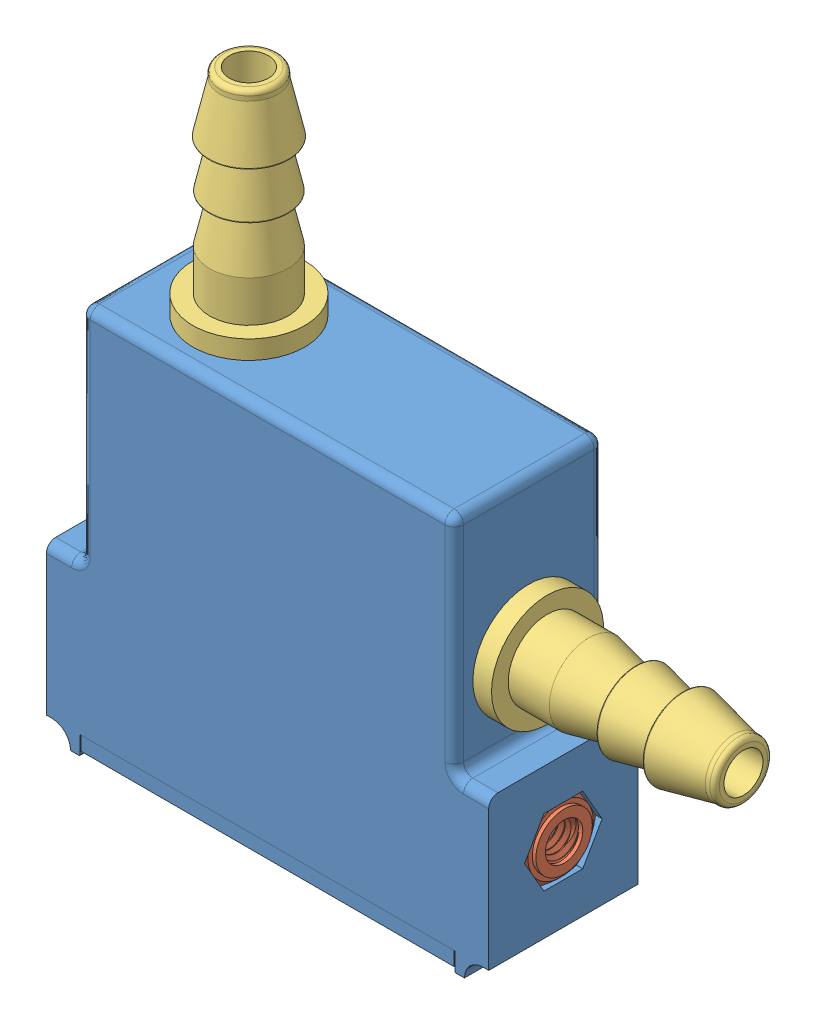
SolidWorks assembly Thermal_Block_Half_Assembly_P, configuration Default. Lengths in mm.
Overall size (66.78 65 16.85).
5 component instances, 3 part files, 8 mates.
Components (placement in the parent):
- Thermal_Block_Half_P-1: Thermal_Block_Half_P [Default] at (18.4797 6.8646 35.2017) size (47.4 42 16)
- M4 x 0.7 Hex Nut-1: M4 x 0.7 Hex Nut [90592A090] at (40.2797 14.8646 35.2017) x (0 -1 0) z (0 0 1) size (7 3.86 8.08)
- M4 x 0.7 Hex Nut-2: M4 x 0.7 Hex Nut [90592A090] at (-3.3203 14.8646 35.2017) x (0 1 0) z (0 0 1) size (7 3.86 8.08)
- Tube_Fitting_Final-1: Tube_Fitting_Final [Default] at (40.4797 30.8646 35.2017) x (1 0 0) z (0 0.787568 -0.616227) size (23 12 12)
- Tube_Fitting_Final-2: Tube_Fitting_Final [Default] at (8.4797 48.8646 35.2017) x (0 1 0) z (0 0 1) size (23 12 12)
Mates (geometry in assembly coordinates):
- Coincident1: coincident anti-aligned: plane of Thermal_Block_Half_P-1 through (38.6797 6.8646 35.2017) normal (1 0 0); plane of M4 x 0.7 Hex Nut-1 through (38.6797 18.3646 33.181) normal (-1 0 0)
- Concentric1: concentric aligned: circle of Thermal_Block_P-1; circle of M4 x 0.7 Hex Nut-1
- Coincident2: coincident anti-aligned: plane of Thermal_Block_Half_P-1 through (-1.7203 6.8646 35.2017) normal (-1 0 0); plane of M4 x 0.7 Hex Nut-2 through (-1.7203 11.3646 33.181) normal (1 0 0)
- Concentric2: concentric anti-aligned: circle of Thermal_Block_P-1; circle of M4 x 0.7 Hex Nut-2
- Parallel1: parallel anti-aligned: plane of Thermal_Block_Half_P-1 through (38.6797 14.8646 39.3586) normal (0 -0.5 -0.866025); plane of M4 x 0.7 Hex Nut-1 through (41.8797 18.3646 37.2224) normal (0 0.5 0.866025)
- Parallel2: parallel anti-aligned: plane of Thermal_Block_Half_P-1 through (-1.7203 18.4646 37.2801) normal (0 -1 0); plane of M4 x 0.7 Hex Nut-2 through (-4.9203 18.3646 37.2224) normal (0 1 0)
- Coincident5: coincident anti-aligned: circle of Thermal_Block_P-1; circle of Tube_Fitting_Final-1
- Coincident6: coincident anti-aligned: circle of Thermal_Block_P-1; circle of Tube_Fitting_Final-2
